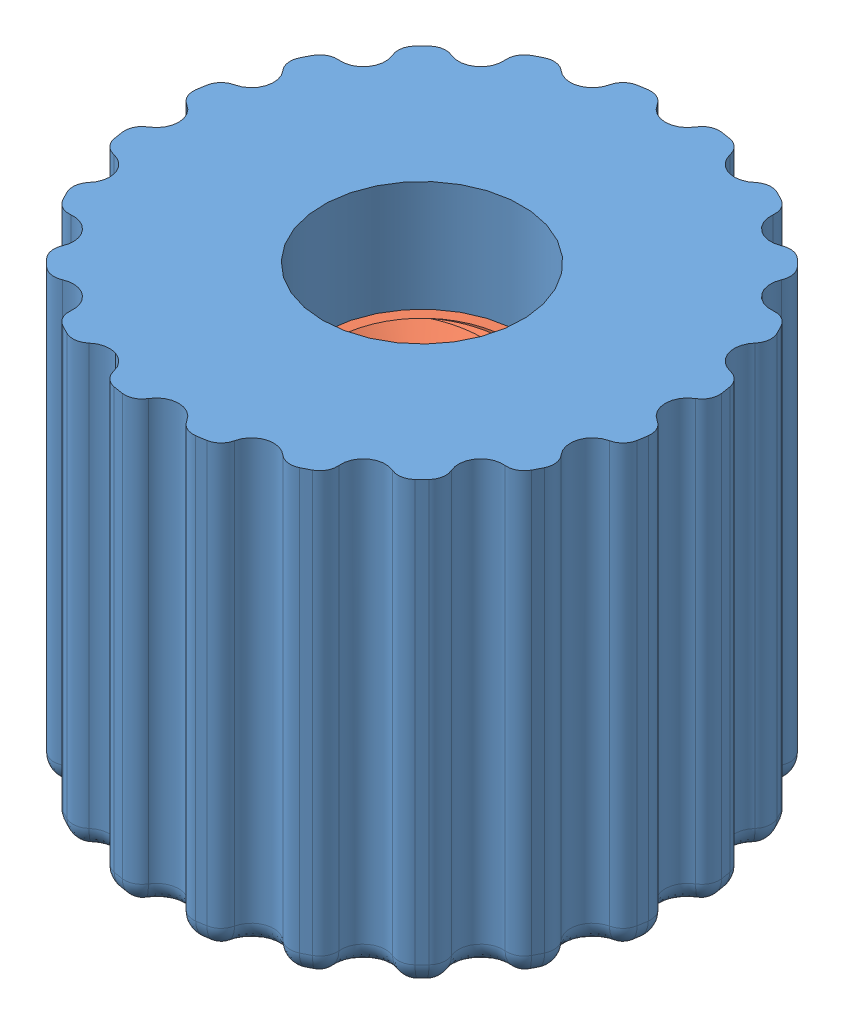
SolidWorks assembly M8_knob_assembly, configuration Default. Lengths in mm.
Overall size (23.87 20.07 23.87).
2 component instances, 2 part files, 3 mates.
Components (placement in the parent):
- knob^M8_knob_assembly-1: knob^M8_knob_assembly [Default] at origin size (23.87 20.07 23.87) (virtual)
- M8 x 1.25 Hex Nut-1: M8 x 1.25 Hex Nut [90592A022] at (0 11.75 0) x (-0.866025 0 -0.5) z (-0.5 0 0.866025) size (13 7.48 15.01)
Mates (geometry in assembly coordinates):
- Concentric1: concentric anti-aligned: circle of knob^M8_knob_assembly-1; circle of M8 x 1.25 Hex Nut-1
- Parallel1: parallel anti-aligned: plane of knob^M8_knob_assembly-1 through (-7.621 15 0) normal (0.866025 0 0.5); plane of M8 x 1.25 Hex Nut-1 through (-7.5056 8.5 0) normal (-0.866025 0 -0.5)
- Coincident2: coincident anti-aligned: plane of knob^M8_knob_assembly-1 through (0 15 0) normal (0 -1 0); plane of M8 x 1.25 Hex Nut-1 through (7.5056 15 0) normal (0 1 0)
